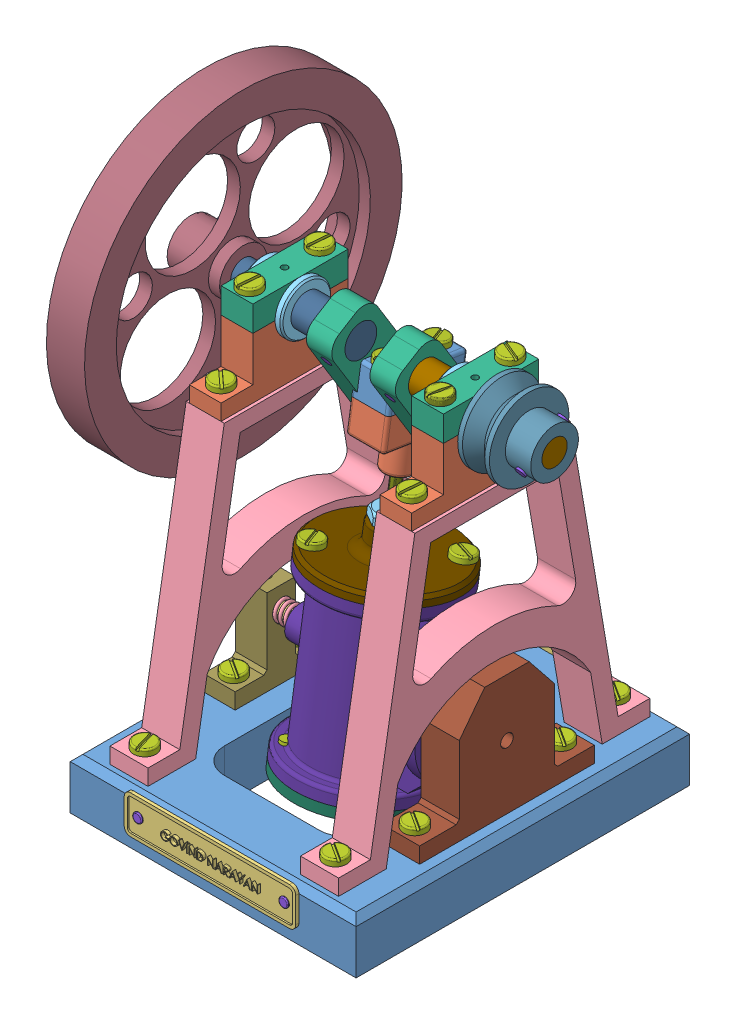
SolidWorks assembly Assem1, configuration Default. Lengths in mm.
Overall size (115 190.78 137.55).
67 component instances, 26 part files, 127 mates.
Components (placement in the parent):
- Part10-1: Part10 [Default] at (52.5102 44.1235 75.3843) size (90 16 105)
- Part11-1: Part11 [Default] at (17.5102 147.1235 75.3843) x (0 0 -1) z (0 -1 0) size (50 10 19)
- Part12-1: Part12 [Default] at (52.5102 54.1235 127.8843) x (1 0 0) z (0 -1 0) size (54 1.5 12)
- Part7-1: Part7 [Default] at (28.5102 65.1235 75.3843) x (0 0 1) z (0 -1 0) size (98 12 87)
- Part7-2: Part7 [Default] at (88.5102 65.1235 75.3843) x (0 0 1) z (0 -1 0) size (98 12 87)
- Part11-2: Part11 [Default] at (77.5102 147.1235 75.3843) x (0 0 -1) z (0 -1 0) size (50 10 19)
- Part9-1: Part9 [Default] at (17.5102 166.1235 75.3843) x (0 -0.123003 0.992406) z (0 0.992406 0.123003) size (16 14 16)
- Part9-2: Part9 [Default] at (77.5102 166.1235 75.3843) x (0 0.164748 0.986336) z (0 0.986336 -0.164748) size (16 14 16)
- Part12-2: Part12 [Default] at (52.5102 54.1235 22.8843) x (-1 0 0) z (0 -1 0) size (54 1.5 12)
- Assem2-1: Assem2 [Default] at (63.2985 125.0208 66.898) x (0 0.52356 -0.851989) z (0 0.851989 0.52356) size (16 115 38)
  - Part14-1: Part14 [Default] at (13.9631 16.7882 12.0828) size (16 8 38)
  - Part15-1: Part15 [Default] at (14.2895 -3.2118 19.4621) x (0 0 1) z (-1 0 0) size (10 28 10)
  - Part16-1: Part16 [Default] at (6.2895 20.7882 19.4621) x (0 0.06317 -0.998003) z (0 -0.998003 -0.06317) size (3 16 3)
  - Part17-1: Part17 [Default] at (14.2895 4.7882 39.4621) x (0 0 -1) z (-1 0 0) size (10 49 10)
  - Part18-1: Part18 [Default] at (14.2895 16.7882 39.4621) x (0 0 -1) z (1 0 0) size (10 54 10)
  - Part14-2: Part14 [Default] at (13.9631 -3.2118 12.0828) size (16 8 38)
  - Part16-2: Part16 [Default] at (6.2895 0.7882 19.4621) x (0 0.06317 -0.998003) z (0 -0.998003 -0.06317) size (3 16 3)
  - Part16-5: Part16 [Default] at (6.2895 0.7882 39.4621) x (0 0.06317 -0.998003) z (0 -0.998003 -0.06317) size (3 16 3)
  - Part16-6: Part16 [Default] at (6.2895 20.7882 39.4621) x (0 0.06317 -0.998003) z (0 -0.998003 -0.06317) size (3 16 3)
- Part21-1: Part21 [Default] at (92.5102 81.6235 75.3843) x (0 0 1) z (0 -1 0) size (55 12 38)
- Part22-1: Part22 [Default] at (21.4815 60.1235 76.9743) x (-0.002483 0 0.999997) z (0 -1 0) size (29 10 27)
- Wheel -1: Wheel  [Default] at (9.5102 166.1235 75.3843) x (0 0.851989 0.52356) z (0 -0.52356 0.851989) size (100 16.5 100)
- Part16-1: Part16 [Default] at (-3.4898 161.935 82.2002) x (0.131059 -0.84464 -0.519044) z (0.991375 0.111661 0.068617) size (3 16 3)
- Pully -1: Pully  [Default] at (94.5102 166.1235 75.3843) x (0 0.851989 0.52356) z (0 0.52356 -0.851989) size (25 22 25)
- Part16-2: Part16 [Default] at (103.5102 161.935 82.2002) x (0.131059 -0.84464 -0.519044) z (0.991375 0.111661 0.068617) size (3 16 3)
- Part13-1: Part13 [Default] at (50.5102 54.4182 79.2875) x (-1 0 0) z (0 0.150123 0.988667) size (42 4 42)
- Part19-1: Part19 [Default] at (50.5102 60.1037 78.4242) x (0.974921 -0.03341 -0.220031) z (0.222553 0.146358 0.963872) size (26 80 26)
- Part4-1: Part4 [Default] at (50.5102 101.8742 72.0816) x (0 0.150123 0.988667) z (-1 0 0) size (42 52 61)
- Part5-1: Part5 [Default] at (50.5102 105.8289 71.4811) x (0 -0.150123 -0.988667) z (1 0 0) size (42 12.53 42)
- Part2-1: Part2 [Default] at (50.5102 149.0837 64.9131) x (0 0.150123 0.988667) z (-1 0 0) size (24 10 12)
- Part3-1: Part3 [Default] at (50.5102 139.1971 66.4144) x (0 0.150123 0.988667) z (-1 0 0) size (24 20 12)
- Nut -1: Nut  [Default] at (4.574 80.1235 75.3547) x (-0.000153 -0.998108 0.061492) z (-0.002478 0.061492 0.998105) size (10 24 10)
- Part20-1: Part20 [Default] at (29.9857 80.3298 75.2766) x (0.000006 -0.999997 -0.002483) z (-0.002483 -0.002483 0.999994) size (6.66 9.1 6.73)
- Part6-1: Part6 [Default] at (50.5102 119.6702 69.3794) x (-0.846304 -0.079971 -0.526663) z (-0.5327 0.12705 0.836713) size (12.7 9.49 10)
- Cap -1: Cap  [Default] at (22.5102 166.1235 75.3843) x (0 0 1) z (-1 0 0) size (30 8 10)
- Nut 2 -1: Nut 2  [Default] at (22.5102 176.1235 64.3843) x (0.995956 0 0.089842) z (-0.089842 0 0.995956) size (7 10.03 7.01)
- Nut 2 -2: Nut 2  [Default] at (22.5102 176.1235 86.3843) x (0.995956 0 0.089842) z (-0.089842 0 0.995956) size (7 10.03 7.01)
- Cap -22: Cap  [Default] at (82.5102 166.1235 75.3843) x (0 0 1) z (-1 0 0) size (30 8 10)
- Nut 2 -43: Nut 2  [Default] at (82.5102 176.1235 86.3843) x (0.995956 0 0.089842) z (-0.089842 0 0.995956) size (7 10.03 7.01)
- Nut 2 -44: Nut 2  [Default] at (82.5102 176.1235 86.3843) x (0.960266 0 0.279087) z (-0.279087 0 0.960266) size (7 10.03 7.01)
- Nut 2 -45: Nut 2  [Default] at (50.5102 159.7468 55.2023) x (0.911309 -0.061809 -0.407056) z (0.411722 0.136809 0.900982) size (7 10.03 7.01)
- Nut 2 -46: Nut 2  [Default] at (50.5102 162.1487 71.021) x (0.985347 0.025605 0.16863) z (-0.170563 0.147923 0.97418) size (7 10.03 7.01)
- Nut 2 -47: Nut 2  [Default] at (82.5102 154.1235 55.3843) x (0.897379 0 -0.44126) z (0.44126 0 0.897379) size (7 10.03 7.01)
- Nut 2 -48: Nut 2  [Default] at (82.5102 176.1235 64.3843) x (-0.384021 0 0.923325) z (-0.923325 0 -0.384021) size (7 10.03 7.01)
- Nut 2 -49: Nut 2  [Default] at (82.5102 154.1235 95.3843) x (0.995956 0 0.089842) z (-0.089842 0 0.995956) size (7 10.03 7.01)
- Nut 2 -50: Nut 2  [Default] at (22.5102 154.1235 95.3843) x (-0.673504 0 0.739183) z (-0.739183 0 -0.673504) size (7 10.03 7.01)
- Nut 2 -51: Nut 2  [Default] at (22.5102 154.1235 55.3843) x (0.177469 0 -0.984126) z (0.984126 0 0.177469) size (7 10.03 7.01)
- Nut 2 -54: Nut 2  [Default] at (38.4894 108.9676 58.8459) x (0.911309 -0.061809 -0.407056) z (0.411722 0.136809 0.900982) size (7 10.03 7.01)
- Nut 2 -55: Nut 2  [Default] at (62.531 108.9676 58.8459) x (-0.332648 0.141574 0.932364) z (-0.943051 -0.049938 -0.328879) size (7 10.03 7.01)
- Nut 2 -56: Nut 2  [Default] at (62.531 112.5768 82.6151) x (0.911309 -0.061809 -0.407056) z (0.411722 0.136809 0.900982) size (7 10.03 7.01)
- Nut 2 -57: Nut 2  [Default] at (38.4894 112.5768 82.6151) x (0.911309 -0.061809 -0.407056) z (0.411722 0.136809 0.900982) size (7 10.03 7.01)
- Nut 2 -58: Nut 2  [Default] at (38.4894 51.2794 91.9227) x (-0.550957 -0.125283 -0.825076) z (-0.834533 0.082711 0.544714) size (7 10.03 7.01)
- Nut 2 -59: Nut 2  [Default] at (38.4894 47.6702 68.1535) x (-0.221968 0.146378 0.964004) z (0.975054 0.033322 0.219452) size (7 10.03 7.01)
- Nut 2 -60: Nut 2  [Default] at (62.531 51.2794 91.9227) x (-0.550957 -0.125283 -0.825076) z (-0.834533 0.082711 0.544714) size (7 10.03 7.01)
- Nut 2 -61: Nut 2  [Default] at (62.531 47.6702 68.1535) x (-0.550957 -0.125283 -0.825076) z (-0.834533 0.082711 0.544714) size (7 10.03 7.01)
- Nut 2 -62: Nut 2  [Default] at (16.5102 67.1235 65.3843) x (-0.540272 0 0.84149) z (-0.84149 0 -0.540272) size (7 10.03 7.01)
- Nut 2 -63: Nut 2  [Default] at (16.5102 67.1235 85.3844) x (-0.540272 0 0.84149) z (-0.84149 0 -0.540272) size (7 10.03 7.01)
- Nut 2 -64: Nut 2  [Default] at (86.5102 67.1235 98.3843) x (-0.540272 0 0.84149) z (-0.84149 0 -0.540272) size (7 10.03 7.01)
- Nut 2 -65: Nut 2  [Default] at (86.5102 67.1235 52.3843) x (-0.540272 0 0.84149) z (-0.84149 0 -0.540272) size (7 10.03 7.01)
- Nut 2 -66: Nut 2  [Default] at (82.5102 67.1235 119.3843) x (-0.540272 0 0.84149) z (-0.84149 0 -0.540272) size (7 10.03 7.01)
- Nut 2 -67: Nut 2  [Default] at (82.5102 67.1235 31.3843) x (-0.540272 0 0.84149) z (-0.84149 0 -0.540272) size (7 10.03 7.01)
- Nut 2 -68: Nut 2  [Default] at (22.5102 67.1235 31.3843) x (-0.993387 0 0.114814) z (-0.114814 0 -0.993387) size (7 10.03 7.01)
- Nut 2 -69: Nut 2  [Default] at (22.5102 67.1235 119.3843) x (-0.959459 0 0.281847) z (-0.281847 0 -0.959459) size (7 10.03 7.01)
- Bolt -1: Bolt  [Default] at (75.5102 54.1235 128.3843) x (1 0 0) z (0 -1 0) size (3 2.5 3)
- Bolt -2: Bolt  [Default] at (29.5102 54.1235 128.3843) x (1 0 0) z (0 -1 0) size (3 2.5 3)
- Bolt -3: Bolt  [Default] at (75.5102 54.1235 22.3843) x (-0.923728 -0.383049 0) z (0.383049 -0.923728 0) size (3 2.5 3)
- Bolt -4: Bolt  [Default] at (29.5102 54.1235 22.3843) x (-0.923728 -0.383049 0) z (0.383049 -0.923728 0) size (3 2.5 3)
Mates (geometry in assembly coordinates):
- Concentric1: concentric anti-aligned: cylinder of Part10-1 through (22.5102 60.1235 31.3843) axis (0 -1 0) radius 1.5; cylinder of Part7-1 through (22.5102 53.1235 31.3843) axis (0 1 0) radius 2
- Concentric2: concentric anti-aligned: cylinder of Part10-1 through (22.5102 60.1235 119.3843) axis (0 -1 0) radius 1.5; cylinder of Part7-1 through (22.5102 53.1235 119.3843) axis (0 1 0) radius 2
- Coincident1: coincident anti-aligned: plane of Part10-1 through (52.5102 60.1235 75.3843) normal (0 1 0); plane of Part7-1 through (16.5102 60.1235 75.3843) normal (0 -1 0)
- Concentric3: concentric anti-aligned: cylinder of Part10-1 through (82.5102 60.1235 119.3843) axis (0 -1 0) radius 1.5; cylinder of Part7-2 through (82.5102 53.1235 119.3843) axis (0 1 0) radius 2
- Concentric4: concentric anti-aligned: cylinder of Part10-1 through (82.5102 60.1235 31.3843) axis (0 -1 0) radius 1.5; cylinder of Part7-2 through (82.5102 53.1235 31.3843) axis (0 1 0) radius 2
- Coincident2: coincident anti-aligned: plane of Part10-1 through (52.5102 60.1235 75.3843) normal (0 1 0); plane of Part7-2 through (76.5102 60.1235 75.3843) normal (0 -1 0)
- Concentric6: concentric anti-aligned: cylinder of Part10-1 through (29.5102 54.1235 117.8843) axis (0 0 1) radius 1.5; cylinder of Part12-1 through (29.5102 54.1235 128.3843) axis (0 0 -1) radius 1
- Concentric7: concentric anti-aligned: cylinder of Part10-1 through (75.5102 54.1235 117.8843) axis (0 0 1) radius 1.5; cylinder of Part12-1 through (75.5102 54.1235 128.3843) axis (0 0 -1) radius 1
- Coincident3: coincident anti-aligned: plane of Part10-1 through (7.5102 60.1235 127.8843) normal (0 0 1); plane of Part12-1 through (52.5102 54.1235 127.8843) normal (0 0 -1)
- Concentric8: concentric aligned: cylinder of Part11-1 through (22.5102 166.1235 95.3843) axis (0 -1 0) radius 2; cylinder of Part7-1 through (22.5102 154.1235 95.3843) axis (0 -1 0) radius 2
- Concentric9: concentric aligned: cylinder of Part11-1 through (22.5102 166.1235 55.3843) axis (0 -1 0) radius 2; cylinder of Part7-1 through (22.5102 154.1235 55.3843) axis (0 -1 0) radius 2
- Coincident4: coincident anti-aligned: plane of Part11-1 through (27.5102 147.1235 50.3843) normal (0 -1 0); plane of Part7-1 through (16.5102 147.1235 75.3843) normal (0 1 0)
- Concentric10: concentric aligned: cylinder of Part7-2 through (82.5102 154.1235 95.3843) axis (0 -1 0) radius 2; cylinder of Part11-2 through (82.5102 166.1235 95.3843) axis (0 -1 0) radius 2
- Concentric11: concentric aligned: cylinder of Part7-2 through (82.5102 154.1235 55.3843) axis (0 -1 0) radius 2; cylinder of Part11-2 through (82.5102 166.1235 55.3843) axis (0 -1 0) radius 2
- Coincident5: coincident anti-aligned: plane of Part7-2 through (76.5102 147.1235 75.3843) normal (0 1 0); plane of Part11-2 through (87.5102 147.1235 50.3843) normal (0 -1 0)
- Concentric12: concentric anti-aligned: cylinder of Part11-1 through (27.5102 166.1235 75.3843) axis (-1 0 0) radius 6; cylinder of Part9-1 through (15.5102 166.1235 75.3843) axis (1 0 0) radius 6
- Width1: width anti-aligned: plane of Part11-1 through (17.5102 166.1235 75.3843) normal (-1 0 0); plane of Part11-1 through (27.5102 166.1235 75.3843) normal (1 0 0); plane of Part9-1 through (17.5102 166.1235 75.3843) normal (1 0 0); plane of Part9-1 through (27.5102 166.1235 75.3843) normal (-1 0 0)
- Concentric13: concentric anti-aligned: cylinder of Part11-2 through (87.5102 166.1235 75.3843) axis (-1 0 0) radius 6; cylinder of Part9-2 through (75.5102 166.1235 75.3843) axis (1 0 0) radius 6
- Width2: width anti-aligned: plane of Part9-2 through (77.5102 166.1235 75.3843) normal (1 0 0); plane of Part9-2 through (87.5102 166.1235 75.3843) normal (-1 0 0); plane of Part11-2 through (77.5102 166.1235 75.3843) normal (-1 0 0); plane of Part11-2 through (87.5102 166.1235 75.3843) normal (1 0 0)
- Concentric14: concentric anti-aligned: cylinder of Part10-1 through (29.5102 54.1235 32.8843) axis (0 0 -1) radius 1.5; cylinder of Part12-2 through (29.5102 54.1235 22.3843) axis (0 0 1) radius 1
- Concentric15: concentric anti-aligned: cylinder of Part10-1 through (75.5102 54.1235 32.8843) axis (0 0 -1) radius 1.5; cylinder of Part12-2 through (75.5102 54.1235 22.3843) axis (0 0 1) radius 1
- Coincident6: coincident anti-aligned: plane of Part10-1 through (7.5102 60.1235 22.8843) normal (0 0 -1); plane of Part12-2 through (52.5102 54.1235 22.8843) normal (0 0 1)
- Concentric17: concentric aligned: cylinder of Part9-1 through (15.5102 166.1235 75.3843) axis (1 0 0) radius 4; cylinder of Assem2-1/Part18-1 through (-7.4898 166.1235 75.3843) axis (1 0 0) radius 4
- Width3: width aligned: plane of Part9-1 through (29.5102 166.1235 75.3843) normal (1 0 0); plane of Assem2-1/Part14-2 through (75.5102 166.1235 75.3843) normal (-1 0 0); plane of Part9-2 through (66.5102 170.2502 74.399) normal (1 0 0); plane of Assem2-1/Part14-1 through (38.5102 170.2502 74.399) normal (-1 0 0)
- Concentric20: concentric aligned: cylinder of Part10-1 through (86.5102 60.1235 98.3843) axis (0 -1 0) radius 1.5; cylinder of Part21-1 through (86.5102 98.1235 98.3843) axis (0 -1 0) radius 2
- Concentric21: concentric aligned: cylinder of Part10-1 through (86.5102 60.1235 52.3843) axis (0 -1 0) radius 1.5; cylinder of Part21-1 through (86.5102 98.1235 52.3843) axis (0 -1 0) radius 2
- Coincident8: coincident anti-aligned: plane of Part10-1 through (52.5102 60.1235 75.3843) normal (0 1 0); plane of Part21-1 through (80.5102 60.1235 47.8843) normal (0 -1 0)
- Concentric30: concentric aligned: cylinder of Part10-1 through (16.5102 60.1235 85.3843) axis (0 -1 0) radius 1.5; cylinder of Part22-1 through (16.5102 70.1235 85.3844) axis (0 -1 0) radius 2
- Concentric31: concentric aligned: cylinder of Part10-1 through (16.5102 60.1235 65.3843) axis (0 -1 0) radius 1.5; cylinder of Part22-1 through (16.5102 70.1235 65.3843) axis (0 -1 0) radius 2
- Coincident9: coincident anti-aligned: plane of Part10-1 through (52.5102 60.1235 75.3843) normal (0 1 0); plane of Part22-1 through (11.4854 60.1235 75.3719) normal (0 -1 0)
- Concentric32: concentric aligned: cylinder of Assem2-1/Part18-1 through (-3.4898 163.5057 79.6443) axis (0 0.52356 -0.851989) radius 1.5; cylinder of Wheel -1 through (-3.4898 160.8879 83.9042) axis (0 0.52356 -0.851989) radius 1.5
- Concentric33: concentric aligned: cylinder of Assem2-1/Part18-1 through (-7.4898 166.1235 75.3843) axis (1 0 0) radius 4; cylinder of Wheel -1 through (-6.9898 166.1235 75.3843) axis (1 0 0) radius 4
- Concentric34: concentric anti-aligned: cylinder of Wheel -1 through (-3.4898 160.8879 83.9042) axis (0 0.52356 -0.851989) radius 1.5; cylinder of Part16-1 through (-3.4898 170.312 68.5684) axis (0 -0.52356 0.851989) radius 1.5
- Width6: width: plane of Part16-1 through (-3.4898 161.935 82.2002) normal (0 -0.52356 0.851989); plane of Wheel -1 through (-3.4898 170.312 68.5684) normal (0 0.52356 -0.851989); cylinder of Part16-1 through (-6.9898 166.1235 75.3843) axis (1 0 0) radius 7.5
- Concentric38: concentric aligned: cylinder of Assem2-1/Part17-1 through (107.5102 166.1235 75.3843) axis (-1 0 0) radius 4; cylinder of Pully -1 through (107.5102 166.1235 75.3843) axis (-1 0 0) radius 4
- Concentric39: concentric anti-aligned: cylinder of Assem2-1/Part17-1 through (103.5102 168.7413 71.1244) axis (0 -0.52356 0.851989) radius 1.5; cylinder of Pully -1 through (103.5102 159.579 86.0342) axis (0 0.52356 -0.851989) radius 1.5
- Width7: width: plane of Part16-2 through (103.5102 161.935 82.2002) normal (0 -0.52356 0.851989); plane of Pully -1 through (103.5102 170.312 68.5684) normal (0 0.52356 -0.851989); cylinder of Part16-2 through (107.5102 166.1235 75.3843) axis (-1 0 0) radius 7.5
- Concentric40: concentric anti-aligned: cylinder of Pully -1 through (103.5102 159.579 86.0342) axis (0 0.52356 -0.851989) radius 1.5; cylinder of Part16-2 through (103.5102 170.312 68.5684) axis (0 -0.52356 0.851989) radius 1.5
- Concentric41: concentric aligned: cylinder of Part13-1 through (62.531 53.2568 91.6225) axis (0 0.988667 -0.150123) radius 2; cylinder of Part4-1 through (62.531 56.2228 91.1721) axis (0 0.988667 -0.150123) radius 2
- Concentric42: concentric aligned: cylinder of Part13-1 through (38.4894 49.6476 67.8533) axis (0 0.988667 -0.150123) radius 2; cylinder of Part4-1 through (38.4894 52.6136 67.4029) axis (0 0.988667 -0.150123) radius 2
- Coincident12: coincident anti-aligned: plane of Part13-1 through (50.5102 54.4182 79.2875) normal (0 0.988667 -0.150123); plane of Part4-1 through (50.5102 54.4182 79.2875) normal (0 -0.988667 0.150123)
- Concentric43: concentric aligned: cylinder of Part19-1 through (50.5102 68.013 77.2232) axis (0 -0.988667 0.150123) radius 12; cylinder of Part4-1 through (50.5102 105.8289 71.4811) axis (0 -0.988667 0.150123) radius 12
- Concentric44: concentric aligned: cylinder of Part4-1 through (62.531 104.0243 59.5965) axis (0 -0.988667 0.150123) radius 2; cylinder of Part5-1 through (62.531 106.9903 59.1462) axis (0 -0.988667 0.150123) radius 2
- Concentric45: concentric aligned: cylinder of Part4-1 through (38.4894 107.6335 83.3657) axis (0 -0.988667 0.150123) radius 2; cylinder of Part5-1 through (38.4894 110.5995 82.9153) axis (0 -0.988667 0.150123) radius 2
- Coincident13: coincident anti-aligned: plane of Part4-1 through (50.5102 105.8289 71.4811) normal (0 0.988667 -0.150123); plane of Part5-1 through (50.5102 105.8289 71.4811) normal (0 -0.988667 0.150123)
- Concentric46: concentric aligned: cylinder of Part2-1 through (50.5102 157.7694 55.5026) axis (0 -0.988667 0.150123) radius 2; cylinder of Part3-1 through (50.5102 147.8827 57.0038) axis (0 -0.988667 0.150123) radius 2
- Concentric47: concentric aligned: cylinder of Part2-1 through (50.5102 160.1714 71.3212) axis (0 -0.988667 0.150123) radius 2; cylinder of Part3-1 through (50.5102 150.2847 72.8225) axis (0 -0.988667 0.150123) radius 2
- Coincident14: coincident anti-aligned: plane of Part2-1 through (50.5102 149.0837 64.9131) normal (0 -0.988667 0.150123); plane of Part3-1 through (50.5102 149.0837 64.9131) normal (0 0.988667 -0.150123)
- Concentric48: concentric aligned: cylinder of Part19-1 through (50.5102 139.1971 66.4144) axis (0 -0.988667 0.150123) radius 1.5; cylinder of Part3-1 through (50.5102 139.1971 66.4144) axis (0 -0.988667 0.150123) radius 2.5
- Coincident15: coincident anti-aligned: plane of Part19-1 through (50.5102 139.1971 66.4144) normal (0 0.988667 -0.150123); plane of Part3-1 through (50.5102 139.1971 66.4144) normal (0 -0.988667 0.150123)
- Concentric49: concentric aligned: cylinder of Part21-1 through (92.5102 80.1235 75.3843) axis (-1 0 0) radius 2; cylinder of Part4-1 through (88.5102 80.1235 75.3843) axis (-1 0 0) radius 2
- Coincident16: coincident anti-aligned: plane of Part21-1 through (80.5102 81.6235 75.3843) normal (-1 0 0); plane of Part4-1 through (80.5102 80.1235 75.3843) normal (1 0 0)
- Concentric50: concentric anti-aligned: cylinder of Part22-1 through (11.4854 80.1235 75.3719) axis (0.999997 0 0.002483) radius 2.5; cylinder of Nut -1 through (26.0739 80.1235 75.4081) axis (-0.999997 0 -0.002483) radius 2.5
- Coincident17: coincident anti-aligned: plane of Part22-1 through (21.4815 60.1235 76.9743) normal (0.999997 0 0.002483); plane of Part20-1 through (21.4857 80.3298 75.2555) normal (-0.999997 0 -0.002483)
- Tangent2: tangent anti-aligned: cylinder of Nut -1 through (26.0739 80.1235 75.4081) axis (-0.999997 0 -0.002483) radius 2.5; face of Part20-1
- Concentric51: concentric anti-aligned: cylinder of Assem2-1/Part15-1 through (38.5102 149.0837 64.9131) axis (1 0 0) radius 4.9995; cylinder of Part3-1 through (56.5102 149.0837 64.9131) axis (-1 0 0) radius 5
- Concentric52: concentric aligned: cylinder of Part19-1 through (50.5102 139.1971 66.4144) axis (0 -0.988667 0.150123) radius 1.5; cylinder of Part6-1 through (50.5102 120.6589 69.2293) axis (0 -0.988667 0.150123) radius 2.5
- Coincident18: coincident anti-aligned: plane of Part5-1 through (50.5102 116.7042 69.8298) normal (0 0.988667 -0.150123); plane of Part6-1 through (50.5102 116.7042 69.8298) normal (0 -0.988667 0.150123)
- Coincident19: coincident anti-aligned: cylinder of Part11-1 through (22.5102 166.1235 86.3843) axis (0 -1 0) radius 2; circle of Cap -1
- Concentric53: concentric aligned: cylinder of Part11-1 through (22.5102 166.1235 64.3843) axis (0 -1 0) radius 2; cylinder of Cap -1 through (22.5102 174.1235 64.3843) axis (0 -1 0) radius 2
- Coincident20: coincident anti-aligned: plane of Part11-1 through (27.5102 166.1235 69.3843) normal (0 1 0); plane of Cap -1 through (22.5102 166.1235 75.3843) normal (0 -1 0)
- Concentric54: concentric anti-aligned: cylinder of Cap -1 through (22.5102 174.1235 64.3843) axis (0 -1 0) radius 2; cylinder of Nut 2 -1 through (22.5102 166.1235 64.3843) axis (0 1 0) radius 2
- Coincident21: coincident anti-aligned: plane of Cap -1 through (22.5102 174.1235 75.3843) normal (0 1 0); plane of Nut 2 -1 through (22.5102 174.1235 64.3843) normal (0 -1 0)
- Concentric551: concentric anti-aligned: cylinder of Cap -1 through (22.5102 174.1235 86.3843) axis (0 -1 0) radius 2; cylinder of Nut 2 -2 through (22.5102 174.1235 86.3843) axis (0 1 0) radius 3.5
- Coincident22: coincident anti-aligned: plane of Cap -1 through (22.5102 174.1235 75.3843) normal (0 1 0); plane of Nut 2 -2 through (22.5102 174.1235 86.3843) normal (0 -1 0)
- Concentric109: concentric aligned: cylinder of Part11-2 through (82.5102 166.1235 64.3843) axis (0 -1 0) radius 2; cylinder of Cap -22 through (82.5102 174.1235 64.3843) axis (0 -1 0) radius 2
- Concentric110: concentric aligned: cylinder of Part11-2 through (82.5102 166.1235 86.3843) axis (0 -1 0) radius 2; cylinder of Cap -22 through (82.5102 174.1235 86.3843) axis (0 -1 0) radius 2
- Coincident96: coincident anti-aligned: plane of Part11-2 through (87.5102 166.1235 90.3843) normal (0 1 0); plane of Cap -22 through (82.5102 166.1235 75.3843) normal (0 -1 0)
- Concentric112: concentric anti-aligned: cylinder of Cap -22 through (82.5102 174.1235 86.3843) axis (0 -1 0) radius 2; cylinder of Nut 2 -43 through (82.5102 166.1235 86.3843) axis (0 1 0) radius 2
- Coincident97: coincident anti-aligned: plane of Cap -22 through (82.5102 174.1235 75.3843) normal (0 1 0); plane of Nut 2 -44 through (82.5102 174.1235 86.3843) normal (0 -1 0)
- Coincident98: coincident anti-aligned: plane of Cap -22 through (82.5102 174.1235 75.3843) normal (0 1 0); plane of Nut 2 -43 through (82.5102 174.1235 86.3843) normal (0 -1 0)
- Concentric113: concentric anti-aligned: circle of Nut 2 -43; circle of Nut 2 -44
- Concentric114: concentric aligned: circle of Nut 2 -43; circle of Nut 2 -44
- Concentric115: concentric anti-aligned: cylinder of Cap -22 through (82.5102 174.1235 64.3843) axis (0 -1 0) radius 2; cylinder of Nut 2 -48 through (82.5102 166.1235 64.3843) axis (0 1 0) radius 2
- Coincident99: coincident anti-aligned: plane of Cap -22 through (82.5102 174.1235 75.3843) normal (0 1 0); plane of Nut 2 -48 through (82.5102 174.1235 64.3843) normal (0 -1 0)
- Concentric117: concentric anti-aligned: cylinder of Part11-2 through (82.5102 166.1235 95.3843) axis (0 -1 0) radius 2; cylinder of Nut 2 -49 through (82.5102 144.1235 95.3843) axis (0 1 0) radius 2
- Coincident100: coincident anti-aligned: plane of Part11-2 through (87.5102 152.1235 100.3843) normal (0 1 0); plane of Nut 2 -49 through (82.5102 152.1235 95.3843) normal (0 -1 0)
- Concentric118: concentric anti-aligned: cylinder of Part11-2 through (82.5102 166.1235 55.3843) axis (0 -1 0) radius 2; cylinder of Nut 2 -47 through (82.5102 144.1235 55.3843) axis (0 1 0) radius 2
- Coincident101: coincident anti-aligned: plane of Part11-2 through (87.5102 152.1235 50.3843) normal (0 1 0); plane of Nut 2 -47 through (82.5102 152.1235 55.3843) normal (0 -1 0)
- Concentric119: concentric anti-aligned: cylinder of Part11-1 through (22.5102 166.1235 95.3843) axis (0 -1 0) radius 2; cylinder of Nut 2 -50 through (22.5102 144.1235 95.3843) axis (0 1 0) radius 2
- Concentric120: concentric anti-aligned: cylinder of Part11-1 through (22.5102 166.1235 55.3843) axis (0 -1 0) radius 2; cylinder of Nut 2 -51 through (22.5102 144.1235 55.3843) axis (0 1 0) radius 2
- Coincident102: coincident anti-aligned: plane of Part11-1 through (27.5102 152.1235 100.3843) normal (0 1 0); plane of Nut 2 -50 through (22.5102 152.1235 95.3843) normal (0 -1 0)
- Coincident103: coincident anti-aligned: plane of Part11-1 through (27.5102 152.1235 50.3843) normal (0 1 0); plane of Nut 2 -51 through (22.5102 152.1235 55.3843) normal (0 -1 0)
- Concentric121: concentric anti-aligned: cylinder of Part2-1 through (50.5102 160.1714 71.3212) axis (0 -0.988667 0.150123) radius 2; cylinder of Nut 2 -46 through (50.5102 152.2621 72.5222) axis (0 0.988667 -0.150123) radius 2
- Concentric122: concentric anti-aligned: cylinder of Part2-1 through (50.5102 157.7694 55.5026) axis (0 -0.988667 0.150123) radius 2; cylinder of Nut 2 -45 through (50.5102 149.8601 56.7035) axis (0 0.988667 -0.150123) radius 2
- Coincident104: coincident anti-aligned: plane of Part2-1 through (50.5102 158.9704 63.4119) normal (0 0.988667 -0.150123); plane of Nut 2 -45 through (50.5102 157.7694 55.5026) normal (0 -0.988667 0.150123)
- Coincident105: coincident anti-aligned: plane of Part2-1 through (50.5102 158.9704 63.4119) normal (0 0.988667 -0.150123); plane of Nut 2 -46 through (50.5102 160.1714 71.3212) normal (0 -0.988667 0.150123)
- Concentric123: concentric anti-aligned: cylinder of Part5-1 through (38.4894 106.9903 59.1462) axis (0 -0.988667 0.150123) radius 2; cylinder of Nut 2 -54 through (38.4894 99.0809 60.3471) axis (0 0.988667 -0.150123) radius 2
- Concentric124: concentric anti-aligned: cylinder of Part5-1 through (62.531 106.9903 59.1462) axis (0 -0.988667 0.150123) radius 2; cylinder of Nut 2 -55 through (62.531 99.0809 60.3471) axis (0 0.988667 -0.150123) radius 2
- Concentric125: concentric anti-aligned: cylinder of Nut 2 -57 through (38.4894 102.6901 84.1163) axis (0 0.988667 -0.150123) radius 2; cylinder of Part5-1 through (38.4894 110.5995 82.9153) axis (0 -0.988667 0.150123) radius 2
- Concentric126: concentric anti-aligned: cylinder of Part5-1 through (62.531 110.5995 82.9153) axis (0 -0.988667 0.150123) radius 2; cylinder of Nut 2 -56 through (62.531 102.6901 84.1163) axis (0 0.988667 -0.150123) radius 2
- Coincident107: coincident anti-aligned: plane of Part5-1 through (50.5102 108.7949 71.0307) normal (0 0.988667 -0.150123); plane of Nut 2 -55 through (62.531 106.9903 59.1462) normal (0 -0.988667 0.150123)
- Coincident108: coincident anti-aligned: plane of Part5-1 through (50.5102 108.7949 71.0307) normal (0 0.988667 -0.150123); plane of Nut 2 -54 through (38.4894 106.9903 59.1462) normal (0 -0.988667 0.150123)
- Coincident109: coincident anti-aligned: plane of Part5-1 through (50.5102 108.7949 71.0307) normal (0 0.988667 -0.150123); plane of Nut 2 -56 through (62.531 110.5995 82.9153) normal (0 -0.988667 0.150123)
- Coincident110: coincident anti-aligned: plane of Part5-1 through (50.5102 108.7949 71.0307) normal (0 0.988667 -0.150123); plane of Nut 2 -57 through (38.4894 110.5995 82.9153) normal (0 -0.988667 0.150123)
- Concentric127: concentric anti-aligned: cylinder of Part13-1 through (62.531 49.6476 67.8533) axis (0 0.988667 -0.150123) radius 2; cylinder of Nut 2 -61 through (62.531 57.5569 66.6523) axis (0 -0.988667 0.150123) radius 2
- Concentric128: concentric anti-aligned: cylinder of Part13-1 through (62.531 53.2568 91.6225) axis (0 0.988667 -0.150123) radius 2; cylinder of Nut 2 -60 through (62.531 61.1661 90.4215) axis (0 -0.988667 0.150123) radius 2
- Concentric129: concentric anti-aligned: cylinder of Part13-1 through (38.4894 49.6476 67.8533) axis (0 0.988667 -0.150123) radius 2; cylinder of Nut 2 -59 through (38.4894 57.5569 66.6523) axis (0 -0.988667 0.150123) radius 2
- Concentric130: concentric anti-aligned: cylinder of Part13-1 through (38.4894 53.2568 91.6225) axis (0 0.988667 -0.150123) radius 2; cylinder of Nut 2 -58 through (38.4894 61.1661 90.4215) axis (0 -0.988667 0.150123) radius 2
- Coincident112: coincident anti-aligned: plane of Part13-1 through (50.5102 51.4522 79.7379) normal (0 -0.988667 0.150123); plane of Nut 2 -59 through (38.4894 49.6476 67.8533) normal (0 0.988667 -0.150123)
- Coincident113: coincident anti-aligned: plane of Part13-1 through (50.5102 51.4522 79.7379) normal (0 -0.988667 0.150123); plane of Nut 2 -61 through (62.531 49.6476 67.8533) normal (0 0.988667 -0.150123)
- Coincident114: coincident anti-aligned: plane of Part13-1 through (50.5102 51.4522 79.7379) normal (0 -0.988667 0.150123); plane of Nut 2 -60 through (62.531 53.2568 91.6225) normal (0 0.988667 -0.150123)
- Coincident115: coincident anti-aligned: plane of Part13-1 through (50.5102 51.4522 79.7379) normal (0 -0.988667 0.150123); plane of Nut 2 -58 through (38.4894 53.2568 91.6225) normal (0 0.988667 -0.150123)
- Concentric131: concentric anti-aligned: cylinder of Part22-1 through (16.5102 70.1235 65.3843) axis (0 -1 0) radius 2; cylinder of Nut 2 -62 through (16.5102 57.1235 65.3843) axis (0 1 0) radius 2
- Coincident116: coincident anti-aligned: plane of Part22-1 through (11.5214 65.1235 60.8719) normal (0 1 0); plane of Nut 2 -62 through (16.5102 65.1235 65.3843) normal (0 -1 0)
- Concentric132: concentric anti-aligned: cylinder of Part22-1 through (16.5102 70.1235 85.3844) axis (0 -1 0) radius 2; cylinder of Nut 2 -63 through (16.5102 57.1235 85.3844) axis (0 1 0) radius 2
- Coincident117: coincident anti-aligned: plane of Part22-1 through (11.4742 65.1235 79.8719) normal (0 1 0); plane of Nut 2 -63 through (16.5102 65.1235 85.3844) normal (0 -1 0)
- Concentric133: concentric anti-aligned: cylinder of Part21-1 through (86.5102 98.1235 52.3843) axis (0 -1 0) radius 2; cylinder of Nut 2 -65 through (86.5102 57.1235 52.3843) axis (0 1 0) radius 2
- Coincident118: coincident anti-aligned: plane of Part21-1 through (80.5102 65.1235 47.8843) normal (0 1 0); plane of Nut 2 -65 through (86.5102 65.1235 52.3843) normal (0 -1 0)
- Concentric134: concentric anti-aligned: cylinder of Part21-1 through (86.5102 98.1235 98.3843) axis (0 -1 0) radius 2; cylinder of Nut 2 -64 through (86.5102 57.1235 98.3843) axis (0 1 0) radius 2
- Coincident119: coincident anti-aligned: plane of Part21-1 through (80.5102 65.1235 90.3843) normal (0 1 0); plane of Nut 2 -64 through (86.5102 65.1235 98.3843) normal (0 -1 0)
- Concentric135: concentric aligned: cylinder of Part7-2 through (82.5102 53.1235 119.3843) axis (0 1 0) radius 2; cylinder of Nut 2 -66 through (82.5102 57.1235 119.3843) axis (0 1 0) radius 2
- Coincident121: coincident anti-aligned: plane of Part7-2 through (76.5102 65.1235 75.3843) normal (0 1 0); plane of Nut 2 -66 through (82.5102 65.1235 119.3843) normal (0 -1 0)
- Concentric136: concentric aligned: cylinder of Part7-2 through (82.5102 53.1235 31.3843) axis (0 1 0) radius 2; cylinder of Nut 2 -67 through (82.5102 57.1235 31.3843) axis (0 1 0) radius 2
- Coincident122: coincident anti-aligned: plane of Part7-2 through (76.5102 65.1235 75.3843) normal (0 1 0); plane of Nut 2 -67 through (82.5102 65.1235 31.3843) normal (0 -1 0)
- Concentric137: concentric aligned: cylinder of Part7-1 through (22.5102 53.1235 31.3843) axis (0 1 0) radius 2; cylinder of Nut 2 -68 through (22.5102 57.1235 31.3843) axis (0 1 0) radius 2
- Coincident123: coincident anti-aligned: plane of Part7-1 through (16.5102 65.1235 75.3843) normal (0 1 0); plane of Nut 2 -68 through (22.5102 65.1235 31.3843) normal (0 -1 0)
- Concentric552: concentric aligned: cylinder of Part7-1 through (22.5102 53.1235 119.3843) axis (0 1 0) radius 2; cylinder of Nut 2 -69 through (22.5102 57.1235 119.3843) axis (0 1 0) radius 2
- Coincident124: coincident anti-aligned: plane of Part7-1 through (16.5102 65.1235 75.3843) normal (0 1 0); plane of Nut 2 -69 through (22.5102 65.1235 119.3843) normal (0 -1 0)
- Concentric554: concentric anti-aligned: cylinder of Part12-1 through (75.5102 54.1235 128.3843) axis (0 0 -1) radius 1; cylinder of Bolt -1 through (75.5102 54.1235 126.3843) axis (0 0 1) radius 1
- Coincident126: coincident anti-aligned: plane of Part12-1 through (52.5102 54.1235 128.3843) normal (0 0 1); plane of Bolt -1 through (75.5102 54.1235 128.3843) normal (0 0 -1)
- Concentric555: concentric anti-aligned: cylinder of Part12-1 through (29.5102 54.1235 128.3843) axis (0 0 -1) radius 1; cylinder of Bolt -2 through (29.5102 54.1235 126.3843) axis (0 0 1) radius 1
- Coincident128: coincident anti-aligned: plane of Part12-1 through (52.5102 54.1235 128.3843) normal (0 0 1); plane of Bolt -2 through (29.5102 54.1235 128.3843) normal (0 0 -1)
- Concentric556: concentric: cylinder of Part12-2 through (75.5102 54.1235 22.3843) axis (0 0 1) radius 1; cylinder of Bolt -3 through (75.5102 54.1235 24.3843) axis (0 0 -1) radius 1
- Concentric557: concentric: cylinder of Part12-2 through (29.5102 54.1235 22.3843) axis (0 0 1) radius 1; cylinder of Bolt -4 through (29.5102 54.1235 24.3843) axis (0 0 -1) radius 1
- Coincident130: coincident anti-aligned: plane of Part12-2 through (52.5102 54.1235 22.3843) normal (0 0 -1); plane of Bolt -4 through (29.5102 54.1235 22.3843) normal (0 0 1)
- Coincident131: coincident anti-aligned: plane of Part12-2 through (52.5102 54.1235 22.3843) normal (0 0 -1); plane of Bolt -3 through (75.5102 54.1235 22.3843) normal (0 0 1)
